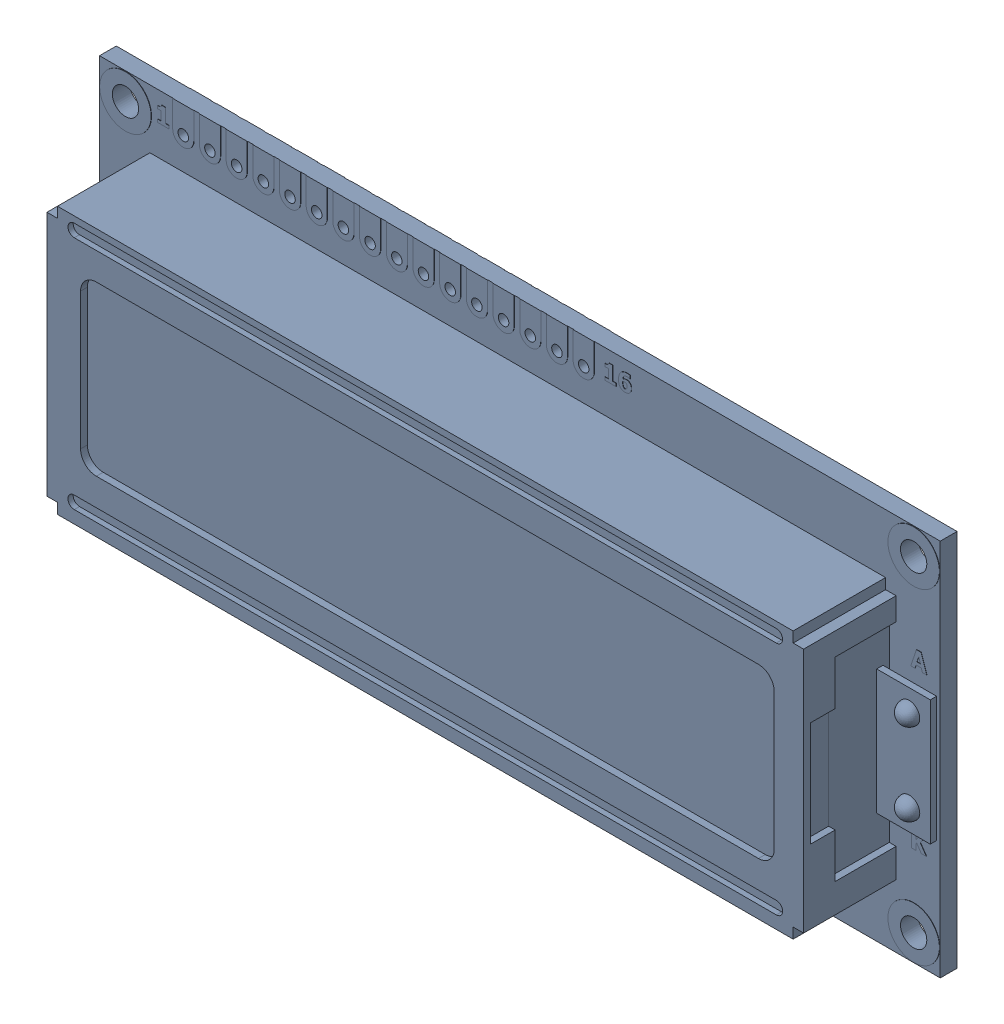
SolidWorks assembly LCD1, configuration Défaut. Lengths in mm.
Overall size (80.25 36 12.9).
2 component instances, 1 part files, 0 mates.
Components (placement in the parent):
- Open CASCADE STEP translator 6.8 1.4.1-1: Open CASCADE STEP translator 6.8 1.4.1 [Défaut] at origin size (80.25 36 12.9)
  - Body_1_3-1: Body_1_3 [Défaut] at (-37.5 -15.4 11) size (80.25 36 12.9)
